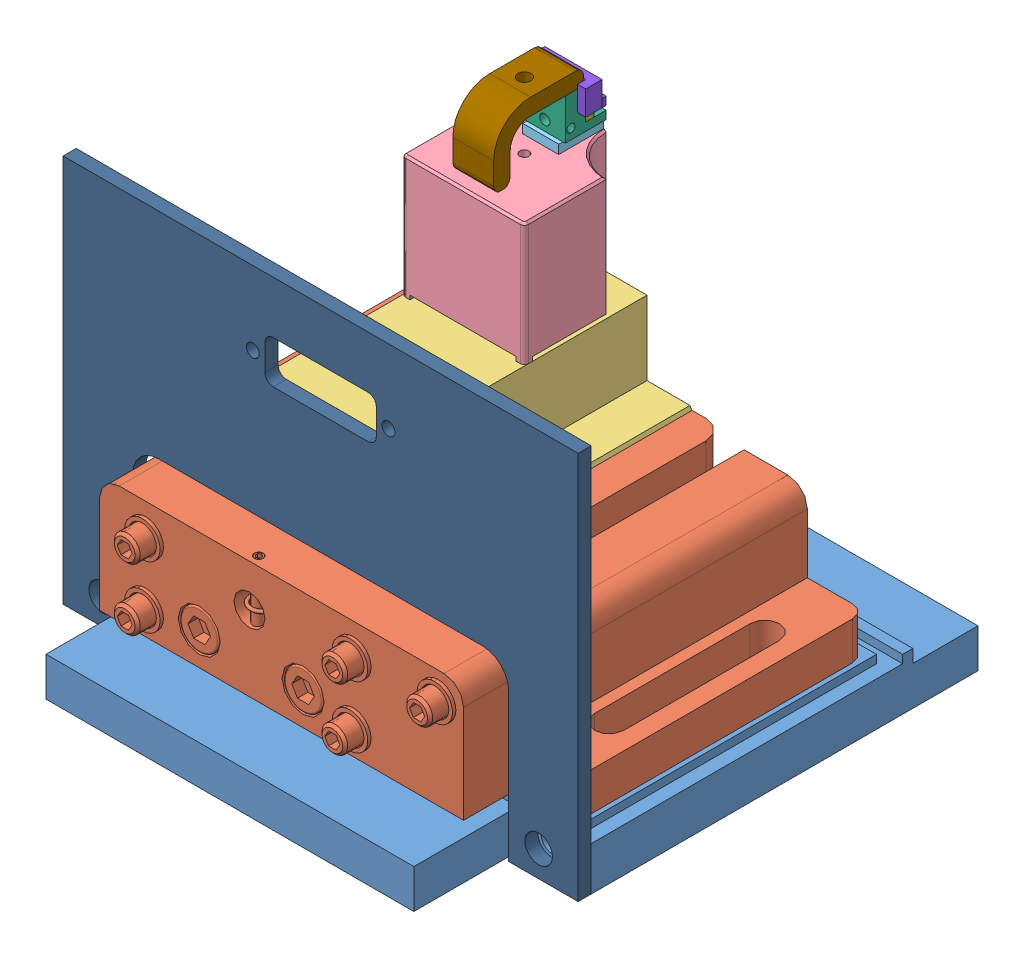
SolidWorks assembly Single SHG Oven Assembly, configuration Default. Lengths in mm.
Overall size (126 110.72 120.04).
10 component instances, 10 part files, 25 mates.
Components (placement in the parent):
- D1201452 Single Oven Riser Plate-1: D1201452 Single Oven Riser Plate [Default] at origin size (126 12.7 120.04)
- newfocus_9082-1: newfocus_9082 [Default] at (1.4629 12.7 -26.7128) size (117.47 32.93 89.26)
- Single Oven SHG Footing-1: Single Oven SHG Footing [Default] at (34.3357 36.9188 40.5034) x (0 0 -1) z (1 0 0) size (65 27.6 58)
- Copper Sink Base-1: Copper Sink Base [Default] at (3.3357 64.5188 -9.4966) x (0 0 -1) z (1 0 0) size (30 30 30)
- Peltier - -HOT20-31-F2A-0909-1: Peltier - -HOT20-31-F2A-0909 [Default] at (-1.0643 94.5188 -13.4966) x (0 0 -1) z (1 0 0) size (11 2.2 8.8)
- Crystal Holder Base-1: Crystal Holder Base [Default] at (-1.6643 96.7188 -14.4966) x (0 0 -1) z (1 0 0) size (10 10 10)
- Crystal-2mm x 1mm x 10mm-1: Crystal-2mm x 1mm x 10mm [Default] at (8.3357 99.2188 -20.4966) x (0 0 1) z (-1 0 0) size (2 1 10)
- Crystal Holder Clamp-1: Crystal Holder Clamp [Default] at (-3.6643 99.7188 -17.4966) x (0 0 -1) z (1 0 0) size (7 8 14)
- Peltier Clamp-1: Peltier Clamp [Default] at (-1.6643 106.7188 -5.9966) size (10 16.4 22)
- D1201453 Single Oven Connector Interface-1: D1201453 Single Oven Connector Interface [Default] at (73.8947 0 44.712) size (126 95 3.2)
Mates (geometry in assembly coordinates):
- Coincident2: coincident anti-aligned: plane of D1201452 Single Oven Riser Plate-1 through (0 12.7 0) normal (0 1 0); plane of newfocus_9082-1 through (10.8482 12.7 8.9996) normal (0 -1 0)
- Coincident3: coincident aligned: plane of D1201452 Single Oven Riser Plate-1 through (-52.1053 12.7 44.712) normal (0 0 1); plane of newfocus_9082-1 through (10.8482 27.0637 44.712) normal (0 0 1)
- Distance1: distance = 1.016 mm aligned: plane of newfocus_9082-1 through (-47.8893 17.3736 8.9996) normal (-1 0 0); plane of D1201452 Single Oven Riser Plate-1 through (-48.9053 10.7 44.712) normal (-1 0 0)
- Coincident7: coincident aligned: line of newfocus_9082-1 through (34.3357 36.9188 40.3339) axis (0 0 -1); line of Single Oven SHG Footing-1 through (34.3357 36.9188 40.5034) axis (0 0 -1)
- Coincident8: coincident aligned: plane of newfocus_9082-1 through (3.0086 37.9729 -24.4966) normal (0 0 -1); plane of Single Oven SHG Footing-1 through (34.3357 46.4188 -24.4966) normal (0 0 -1)
- Coincident9: coincident anti-aligned: plane of Single Oven SHG Footing-1 through (-11.6643 64.5188 -59.5339) normal (0 1 0); plane of Copper Sink Base-1 through (3.3357 64.5188 -9.4966) normal (0 -1 0)
- Coincident10: coincident aligned: plane of Single Oven SHG Footing-1 through (34.3357 46.4188 -24.4966) normal (0 0 -1); plane of Copper Sink Base-1 through (-11.6643 94.5188 -24.4966) normal (0 0 -1)
- Concentric2: concentric aligned: cylinder of Single Oven SHG Footing-1 through (3.3357 36.9188 -9.4966) axis (0 1 0) radius 2.1; cylinder of Copper Sink Base-1 through (3.3357 94.5188 -9.4966) axis (0 1 0) radius 1.25
- Coincident11: coincident anti-aligned: plane of Copper Sink Base-1 through (3.3357 94.5188 -9.4966) normal (0 1 0); plane of Peltier - -HOT20-31-F2A-0909-1 through (-1.0643 94.5188 -13.4966) normal (0 -1 0)
- Coincident12: coincident aligned: plane of Copper Sink Base-1 through (-11.6643 94.5188 -24.4966) normal (0 0 -1); plane of Peltier - -HOT20-31-F2A-0909-1 through (-1.0643 96.7188 -24.4966) normal (0 0 -1)
- Coincident13: coincident aligned: plane of Copper Sink Base-1 through (3.3357 64.5188 -9.4966) normal (1 0 0); plane of Peltier - -HOT20-31-F2A-0909-1 through (3.3357 94.5188 -13.4966) normal (1 0 0)
- Coincident14: coincident anti-aligned: plane of Peltier - -HOT20-31-F2A-0909-1 through (-1.0643 96.7188 -13.4966) normal (0 1 0); plane of Crystal Holder Base-1 through (8.3357 96.7188 -14.4966) normal (0 -1 0)
- Coincident15: coincident aligned: plane of Peltier - -HOT20-31-F2A-0909-1 through (-1.0643 96.7188 -24.4966) normal (0 0 -1); plane of Crystal Holder Base-1 through (8.3357 96.7188 -24.4966) normal (0 0 -1)
- Coincident16: coincident anti-aligned: plane of Peltier - -HOT20-31-F2A-0909-1 through (3.3357 94.5188 -13.4966) normal (1 0 0); plane of Crystal Holder Base-1 through (3.3357 96.7188 -14.4966) normal (-1 0 0)
- Coincident17: coincident anti-aligned: plane of Crystal Holder Base-1 through (-1.6643 98.7188 -24.4966) normal (0 1 0); plane of Crystal-2mm x 1mm x 10mm-1 through (-1.6643 98.7188 -19.4966) normal (0 -1 0)
- Coincident18: coincident anti-aligned: plane of Crystal Holder Base-1 through (-1.6643 106.7188 -19.4966) normal (0 0 -1); plane of Crystal-2mm x 1mm x 10mm-1 through (-1.6643 99.7188 -19.4966) normal (0 0 1)
- Coincident19: coincident aligned: plane of Crystal Holder Base-1 through (8.3357 106.7188 -14.4966) normal (1 0 0); plane of Crystal-2mm x 1mm x 10mm-1 through (8.3357 99.2188 -20.4966) normal (1 0 0)
- Coincident20: coincident anti-aligned: plane of Crystal-2mm x 1mm x 10mm-1 through (-1.6643 99.7188 -19.4966) normal (0 1 0); plane of Crystal Holder Clamp-1 through (10.3357 99.7188 -17.4966) normal (0 -1 0)
- Coincident21: coincident anti-aligned: plane of Crystal Holder Base-1 through (-1.6643 106.7188 -19.4966) normal (0 0 -1); plane of Crystal Holder Clamp-1 through (-1.6643 99.7188 -19.4966) normal (0 0 1)
- Coincident22: coincident aligned: plane of Crystal Holder Base-1 through (3.3357 96.7188 -14.4966) normal (-1 0 0); plane of Crystal Holder Clamp-1 through (3.3357 99.7188 -17.4966) normal (-1 0 0)
- Coincident23: coincident anti-aligned: plane of Crystal Holder Base-1 through (8.3357 106.7188 -14.4966) normal (0 1 0); plane of Peltier Clamp-1 through (8.3357 106.7188 -5.9966) normal (0 -1 0)
- Concentric3: concentric aligned: cylinder of Copper Sink Base-1 through (3.3357 94.5188 -9.4966) axis (0 1 0) radius 1.25; cylinder of Peltier Clamp-1 through (3.3357 100.7188 -9.4966) axis (0 1 0) radius 1.6
- Coincident24: coincident aligned: plane of D1201452 Single Oven Riser Plate-1 through (0 0 0) normal (0 -1 0); plane of D1201453 Single Oven Connector Interface-1 through (73.8947 0 47.912) normal (0 -1 0)
- Coincident25: coincident anti-aligned: plane of D1201452 Single Oven Riser Plate-1 through (-52.1053 12.7 44.712) normal (0 0 1); plane of D1201453 Single Oven Connector Interface-1 through (73.8947 0 44.712) normal (0 0 -1)
- Coincident26: coincident aligned: plane of D1201452 Single Oven Riser Plate-1 through (73.8947 12.7 -31.488) normal (1 0 0); plane of D1201453 Single Oven Connector Interface-1 through (73.8947 0 47.912) normal (1 0 0)
